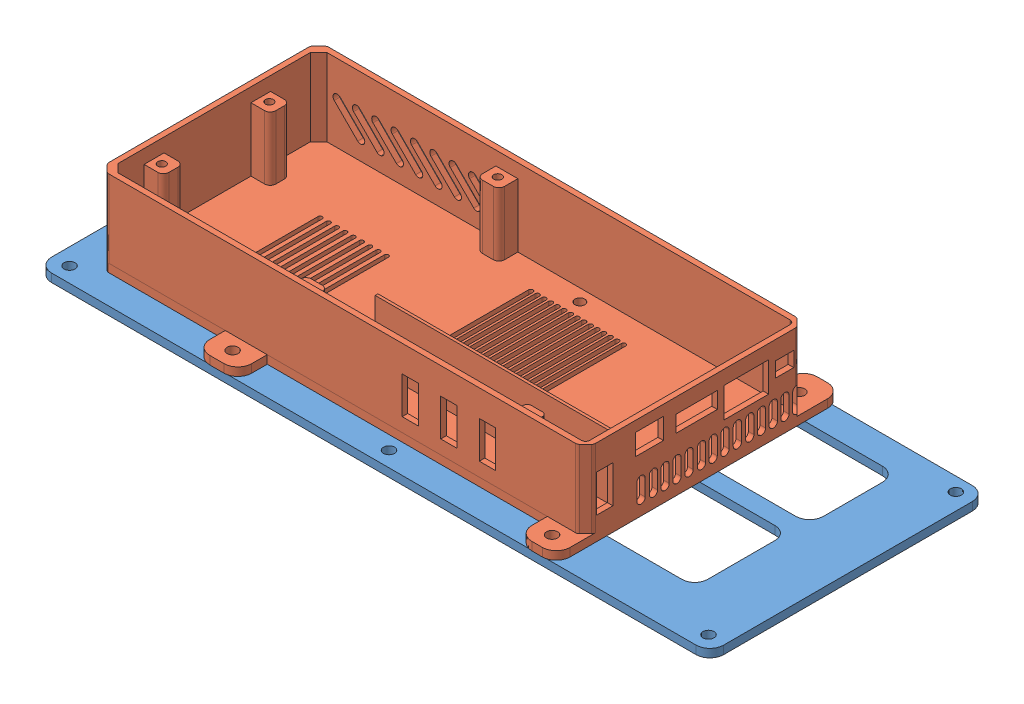
SolidWorks assembly 机器人装配, configuration 默认. Lengths in mm.
Overall size (243.2 34 103.21).
2 component instances, 2 part files, 2 mates.
Components (placement in the parent):
- 银星机器人电路板转接板-1: 银星机器人电路板转接板 [Default] at (-138.3032 8.7073 193.2) size (243.2 3 100)
- RK3588支架-1: RK3588支架 [Default] at (-51.5048 11.7073 444.0541) x (0 0 -1) z (1 0 0) size (103.21 31 176.1)
Mates (geometry in assembly coordinates):
- 同心1: concentric aligned: cylinder of 银星机器人电路板转接板-1 through (41.2981 11.7073 198.2) axis (0 -1 0) radius 2; cylinder of RK3588支架-1 through (41.2981 14.7073 198.2) axis (0 -1 0) radius 2
- 同心2: concentric aligned: cylinder of 银星机器人电路板转接板-1 through (41.2981 11.7073 287.7) axis (0 -1 0) radius 2; cylinder of RK3588支架-1 through (41.2981 14.7073 287.7) axis (0 -1 0) radius 2
